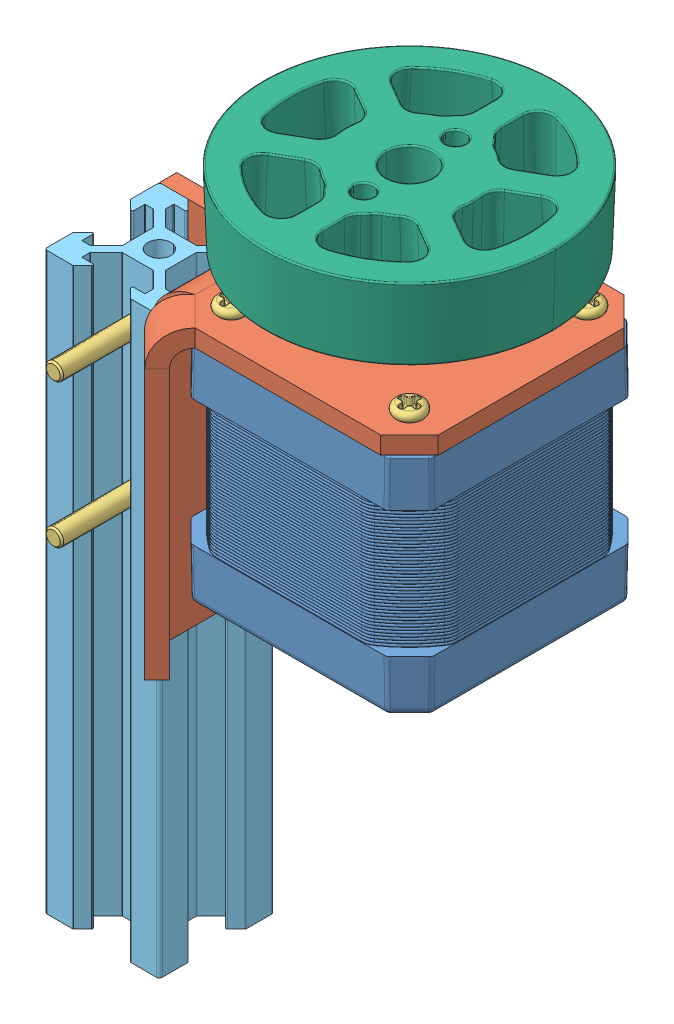
SolidWorks assembly Working Model, configuration Default. Lengths in mm.
Overall size (72.75 128.37 52.54).
11 component instances, 6 part files, 23 mates.
Components (placement in the parent):
- Nema 17 Stepper Motor-1: Nema 17 Stepper Motor [Default] at (-5.7555 12.998 57.6778) size (42 55.5 48)
- Stepper Motor Mount 2020E-1: Stepper Motor Mount 2020E [Default] at (-33.6829 42.998 88.1395) x (0 0 -1) z (0 -1 0) size (46.69 68.51 53.41)
- Screw-1: Screw [Default] at (-21.2555 46.0358 42.1778) size (5 33.46 5)
- Screw-2: Screw [Default] at (-21.2555 46.0358 73.1778) size (5 33.46 5)
- Screw-3: Screw [Default] at (9.7445 46.0358 42.1778) size (5 33.46 5)
- Screw-4: Screw [Default] at (9.7445 46.0358 73.1778) size (5 33.46 5)
- am-3669 5mm Single Boss Hex Nub with Set Screw REV2-1: am-3669 5mm Single Boss Hex Nub with Set Screw REV2 [Default] at (-6.5326 39.2356 66.3275) x (0.987388 0 -0.158321) z (0 1 0) size (16 17 10)
- 20 X 20 mm Extrusion Sample Part MK1.step-1: 20 X 20 mm Extrusion Sample Part MK1.step [Default] at (-53.1183 39.823 73.8278) x (0 0 -1) z (0 -1 0) size (20 20 100)
- Screw-6: Screw [Default] at (-43.1183 5.498 50.79) x (1 0 0) z (0 1 0) size (5 33.46 5)
- Screw-7: Screw [Default] at (-43.1183 30.498 50.79) x (1 0 0) z (0 1 0) size (5 33.46 5)
- am-3572 2IN 8mm Compliant Wheel REV2-1: am-3572 2IN 8mm Compliant Wheel REV2 [Default] at (-5.7555 68.1949 57.6778) x (1 0 0) z (0 -1 0) size (50.78 50.78 12.7)
Mates (geometry in assembly coordinates):
- Coincident1: coincident anti-aligned: plane of Nema 17 Stepper Motor-1 through (-5.7555 42.998 57.6778) normal (0 1 0); plane of Stepper Motor Mount 2020E-1 through (-33.6829 42.998 88.1395) normal (0 -1 0)
- Concentric1: concentric aligned: cylinder of Nema 17 Stepper Motor-1 through (-5.7555 59.498 57.6778) axis (0 -1 0) radius 2.5; cylinder of Stepper Motor Mount 2020E-1 through (-5.7555 46.0358 57.6778) axis (0 -1 0) radius 11
- Concentric2: concentric aligned: cylinder of Nema 17 Stepper Motor-1 through (9.7445 44.998 42.1778) axis (0 -1 0) radius 1.5; cylinder of Stepper Motor Mount 2020E-1 through (9.7445 46.0358 42.1778) axis (0 -1 0) radius 1.5
- Coincident2: coincident anti-aligned: plane of Stepper Motor Mount 2020E-1 through (-33.6829 46.0358 88.1395) normal (0 1 0); plane of Screw-1 through (-19.7555 46.0358 42.1778) normal (0 -1 0)
- Concentric4: concentric aligned: cylinder of Stepper Motor Mount 2020E-1 through (-21.2555 46.0358 42.1778) axis (0 -1 0) radius 1.5; cylinder of Screw-1 through (-21.2555 14.5358 42.1778) axis (0 -1 0) radius 1.5
- Coincident6: coincident anti-aligned: plane of Stepper Motor Mount 2020E-1 through (-33.6829 46.0358 88.1395) normal (0 1 0); plane of Screw-2 through (-19.7555 46.0358 73.1778) normal (0 -1 0)
- Concentric5: concentric aligned: cylinder of Stepper Motor Mount 2020E-1 through (-21.2555 46.0358 73.1778) axis (0 -1 0) radius 1.5; cylinder of Screw-2 through (-21.2555 14.5358 73.1778) axis (0 -1 0) radius 1.5
- Coincident7: coincident anti-aligned: plane of Stepper Motor Mount 2020E-1 through (-33.6829 46.0358 88.1395) normal (0 1 0); plane of Screw-4 through (11.2445 46.0358 73.1778) normal (0 -1 0)
- Concentric6: concentric aligned: cylinder of Stepper Motor Mount 2020E-1 through (9.7445 46.0358 73.1778) axis (0 -1 0) radius 1.5; cylinder of Screw-4 through (9.7445 14.5358 73.1778) axis (0 -1 0) radius 1.5
- Coincident8: coincident anti-aligned: plane of Stepper Motor Mount 2020E-1 through (-33.6829 46.0358 88.1395) normal (0 1 0); plane of Screw-3 through (11.2445 46.0358 42.1778) normal (0 -1 0)
- Concentric7: concentric aligned: cylinder of Stepper Motor Mount 2020E-1 through (9.7445 46.0358 42.1778) axis (0 -1 0) radius 1.5; cylinder of Screw-3 through (9.7445 14.5358 42.1778) axis (0 -1 0) radius 1.5
- Parallel1: parallel anti-aligned: plane of Stepper Motor Mount 2020E-1 through (-33.6829 46.0358 88.1395) normal (0 1 0); plane of am-3669 5mm Single Boss Hex Nub with Set Screw REV2-1 through (-0.9898 48.4949 49.4585) normal (0 -1 0)
- Concentric8: concentric aligned: circle of Stepper Motor Mount 2020E-1; cylinder of am-3669 5mm Single Boss Hex Nub with Set Screw REV2-1 through (-5.7555 58.4949 57.6778) axis (0 -1 0) radius 4
- Parallel2: parallel aligned: plane of Nema 17 Stepper Motor-1 through (-4.591 45.498 55.4656) normal (-0.158321 0 -0.987388); plane of am-3669 5mm Single Boss Hex Nub with Set Screw REV2-1 through (-13.0914 73.8949 50.7519) normal (-0.158321 0 -0.987388)
- Coincident14: coincident anti-aligned: plane of Stepper Motor Mount 2020E-1 through (-33.6829 42.998 53.8278) normal (0 0 1); plane of 20 X 20 mm Extrusion Sample Part MK1.step-1 through (-38.1183 39.823 53.8278) normal (0 0 -1)
- Coincident15: coincident anti-aligned: plane of Stepper Motor Mount 2020E-1 through (-33.1183 42.998 88.1395) normal (-1 0 0); plane of 20 X 20 mm Extrusion Sample Part MK1.step-1 through (-33.1183 39.823 68.8278) normal (1 0 0)
- Coincident16: coincident aligned: plane of Stepper Motor Mount 2020E-1 through (-33.1183 39.823 50.79) normal (0 1 0); plane of 20 X 20 mm Extrusion Sample Part MK1.step-1 through (-43.1183 39.823 63.8278) normal (0 1 0)
- Concentric15: concentric anti-aligned: cylinder of Stepper Motor Mount 2020E-1 through (-43.1183 30.498 60.79) axis (0 0 -1) radius 2; cylinder of Screw-7 through (-43.1183 30.498 82.29) axis (0 0 1) radius 1.5
- Concentric16: concentric anti-aligned: cylinder of Stepper Motor Mount 2020E-1 through (-43.1183 5.498 60.79) axis (0 0 -1) radius 2; cylinder of Screw-6 through (-43.1183 5.498 82.29) axis (0 0 1) radius 1.5
- Coincident17: coincident anti-aligned: plane of Stepper Motor Mount 2020E-1 through (-33.6829 42.998 50.79) normal (0 0 -1); plane of Screw-7 through (-41.6183 30.498 50.79) normal (0 0 1)
- Coincident18: coincident anti-aligned: plane of Stepper Motor Mount 2020E-1 through (-33.6829 42.998 50.79) normal (0 0 -1); plane of Screw-6 through (-41.6183 5.498 50.79) normal (0 0 1)
- Concentric17: concentric anti-aligned: cylinder of am-3669 5mm Single Boss Hex Nub with Set Screw REV2-1 through (-5.7555 58.4949 57.6778) axis (0 -1 0) radius 4; cylinder of am-3572 2IN 8mm Compliant Wheel REV2-1 through (-5.7555 55.4949 57.6778) axis (0 1 0) radius 4
- Coincident19: coincident anti-aligned: plane of am-3669 5mm Single Boss Hex Nub with Set Screw REV2-1 through (-14.9211 55.4949 51.0453) normal (0 1 0); plane of am-3572 2IN 8mm Compliant Wheel REV2-1 through (-5.7555 55.4949 57.6778) normal (0 -1 0)
